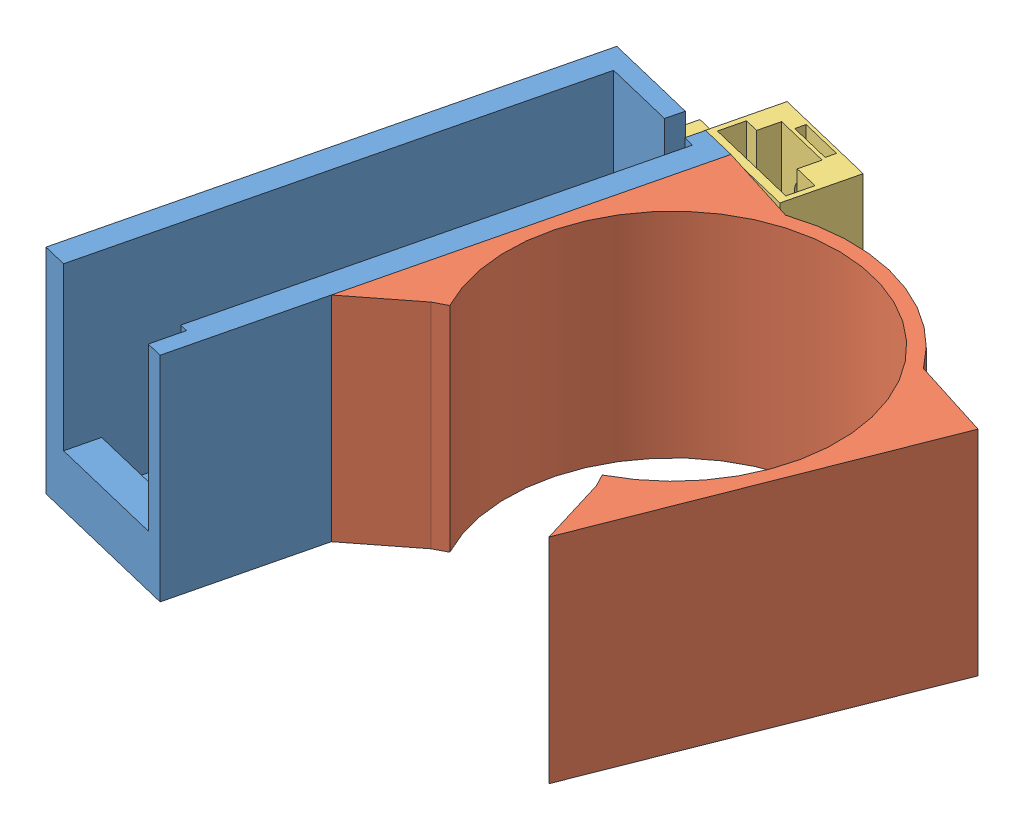
SolidWorks assembly shoe model 5, configuration Default. Lengths in mm.
Overall size (210.03 62 189.94).
4 component instances, 3 part files, 8 mates.
Components (placement in the parent):
- pi_holderSLDPRT-3: pi_holderSLDPRT [Default] at (69.6485 -2.1751 -80.9149) x (0.235993 0 -0.971755) z (0.971755 0 0.235993) size (137.14 62 45)
- cycle-3: cycle [Default] at (141.7725 -2.1751 -157.5558) x (0.887458 0 -0.460889) z (0.460889 0 0.887458) size (140.87 62 140.87)
- camera holder 2.0-5: camera holder 2.0 [Default] at (62.956 7.0323 -244.2506) x (-0.235993 0 0.971755) z (-0.971755 0 -0.235993) size (20 27 30)
- camera holder 2.0-8: camera holder 2.0 [Default] at (96.3478 32.3011 -236.1413) x (-0.235993 0 0.971755) z (-0.971755 0 -0.235993) size (20 27 30)
Mates (geometry in assembly coordinates):
- Coincident17: coincident anti-aligned: plane of pi_holderSLDPRT-3 through (69.6485 59.8249 -80.9149) normal (0.971755 0 0.235993); plane of cycle-3 through (79.3579 59.8249 -120.8956) normal (-0.971755 0 -0.235993)
- Parallel7: parallel aligned: plane of pi_holderSLDPRT-3 through (69.6485 -2.1751 -80.9149) normal (0 -1 0); plane of cycle-3 through (141.7725 -2.1751 -157.5558) normal (0 -1 0)
- Coincident20: coincident anti-aligned: plane of pi_holderSLDPRT-3 through (102.0133 59.8249 -214.1841) normal (0.235993 0 -0.971755); plane of camera holder 2.0-5 through (58.2361 7.0323 -224.8155) normal (-0.235993 0 0.971755)
- Parallel9: parallel aligned: plane of pi_holderSLDPRT-3 through (69.6485 59.8249 -80.9149) normal (0 1 0); plane of cycle-3 through (141.7725 59.8249 -157.5558) normal (0 1 0)
- Coincident25: coincident anti-aligned: plane of pi_holderSLDPRT-3 through (102.0133 59.8249 -214.1841) normal (0.235993 0 -0.971755); plane of camera holder 2.0-8 through (91.628 32.3011 -216.7062) normal (-0.235993 0 0.971755)
- Coincident26: coincident aligned: plane of pi_holderSLDPRT-3 through (69.6485 -2.1751 -80.9149) normal (0 -1 0); plane of cycle-3 through (141.7725 -2.1751 -157.5558) normal (0 -1 0)
- Coincident27: coincident: line of pi_holderSLDPRT-3 through (102.0133 59.8249 -214.1841) axis (0 -1 0); plane of cycle-3 through (125.3722 67.5346 -206.7942) normal (0.30163 0 -0.953425)
- Parallel11: parallel aligned: plane of pi_holderSLDPRT-3 through (69.6485 -2.1751 -80.9149) normal (0 -1 0); plane of camera holder 2.0-8 through (91.628 32.3011 -216.7062) normal (0 -1 0)
